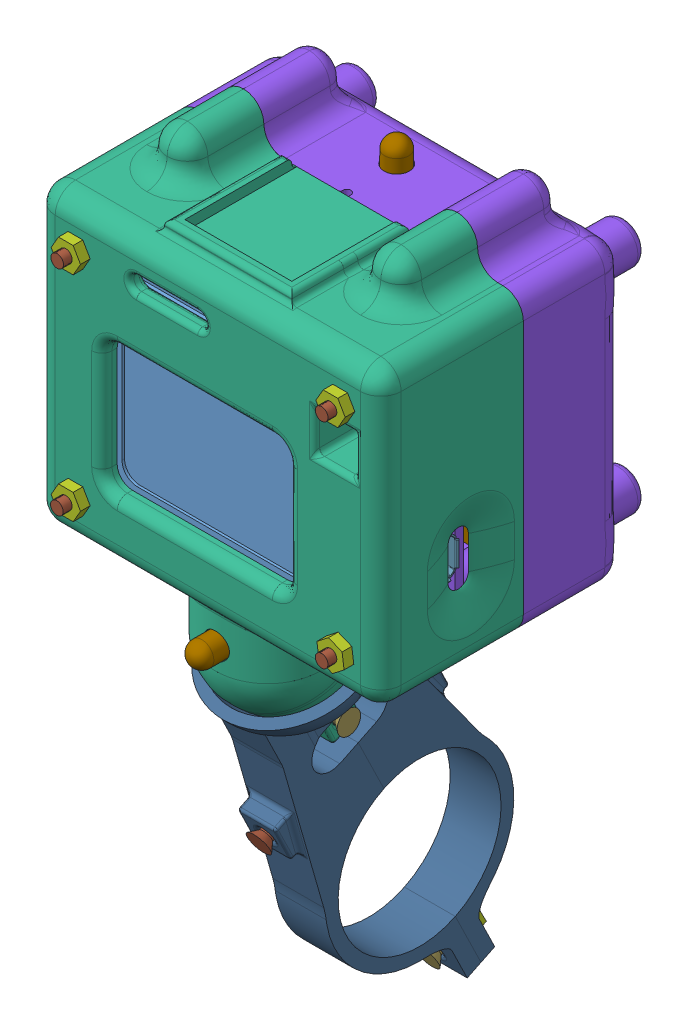
SolidWorks assembly 外壳装配体, configuration 默认. Lengths in mm.
Overall size (68.01 154.06 68.95).
141 component instances, 29 part files, 72 mates.
Components (placement in the parent):
- LCD5110-1: LCD5110 [默认] at (0 0 1.2) size (42.32 45.5 15)
- GPS-1: GPS [默认] x (-1 0 0) z (0 0 -1) size (16 13.5 12.2)
- SIM800L-1: SIM800L [默认] x (-1 0 0) z (0 0 -1) size (40 27.78 12.6)
- M3双通铜柱-1: M3双通铜柱 [默认] at (-25.1238 -0.1501 1.2) size (4.59 5.3 11.22)
- M3双通铜柱-2: M3双通铜柱 [默认] at (16.8947 -71.0684 1.2) x (0.866025 0.5 0) z (0 0 1) size (4.59 5.3 11.22)
- M3双通铜柱-3: M3双通铜柱 [默认] at (60.3287 -26.8877 1.2) x (0.242096 0.970252 0) z (0 0 1) size (4.59 5.3 11.22)
- M3双通铜柱-4: M3双通铜柱 [默认] at (-33.2302 -25.3619 -11) size (4.59 5.3 11.22)
- M3双通铜柱-5: M3双通铜柱 [默认] at (73.8252 -17.7107 -11) x (0 1 0) z (0 0 1) size (4.59 5.3 11.22)
- M3双通铜柱-6: M3双通铜柱 [默认] at (-17.5653 -71.0684 1.2) x (0.866025 0.5 0) z (0 0 1) size (4.59 5.3 11.22)
- M3双通铜柱-7: M3双通铜柱 [默认] at (8.7882 -34.0691 -11) x (0.866025 0.5 0) z (0 0 1) size (4.59 5.3 11.22)
- M3x3-1: M3x3 [默认] at (17.4869 22.3607 12.2) x (1 0 0) z (0 1 0) size (6 4.18 6)
- M3x3-2: M3x3 [默认] at (51.9469 22.3607 12.2) x (1 0 0) z (0 1 0) size (6 4.18 6)
- M3x3-3: M3x3 [默认] at (43.8405 59.3599 -11.6) x (1 0 0) z (0 -1 0) size (6 4.18 6)
- M3x3-4: M3x3 [默认] at (43.8405 38.0239 -11.6) x (1 0 0) z (0 -1 0) size (6 4.18 6)
- M3x3-5: M3x3 [默认] at (10.4394 59.3599 -11.6) x (1 0 0) z (0 -1 0) size (6 4.18 6)
- M3x3-6: M3x3 [默认] at (43.8405 59.3599 0.2) x (1 0 0) z (0 1 0) size (6 4.18 6)
- M3x3-7: M3x3 [默认] at (10.4394 59.3599 0.2) x (1 0 0) z (0 1 0) size (6 4.18 6)
- M3x3-8: M3x3 [默认] at (43.8405 38.0239 0.2) x (1 0 0) z (0 1 0) size (6 4.18 6)
- M3x3-9: M3x3 [默认] at (17.4869 22.3607 1) x (1 0 0) z (0 -1 0) size (6 4.18 6)
- M3x3-10: M3x3 [默认] at (17.4869 63.2357 1) x (1 0 0) z (0 -1 0) size (6 4.18 6)
- M3x3-11: M3x3 [默认] at (51.9469 63.2357 1) x (1 0 0) z (0 -1 0) size (6 4.18 6)
- M3x3-12: M3x3 [默认] at (51.9469 22.3607 1) x (1 0 0) z (0 -1 0) size (6 4.18 6)
- 外壳-上-1: 外壳-上 [默认] at (0.051 -0.0812 1.2) size (68.01 96.44 34)
- M2.5螺母-1: M2.5螺母 [默认] at (63.051 23.9188 20.2) x (-0.926094 0.377293 0) z (0 0 1) size (5.77 5 1.9)
- M2.5螺母-3: M2.5螺母 [默认] at (63.051 65.9188 20.2) size (5.77 5 1.9)
- 外壳-下-1: 外壳-下 [默认] at (0.051 -0.0812 -7.8) x (-1 0 0) z (0 0 -1) size (67.97 73.97 35.69)
- SIM天线-1: SIM天线 [默认] at (56.801 27.4315 -24.8) x (0 0 -1) z (-1 0 0) size (10.5 53 28.75)
- GPS天线-1: GPS天线 [默认] at (16.7214 57.8639 -16.8) x (-1 0 0) z (0 0 -1) size (28 27 8)
- M2.5x60-1: M2.5x60 [默认] at (63.051 65.9188 -26.1568) x (0 0 -1) z (0.717913 -0.696133 0) size (60 4.6 4.6)
- M2.5x60-2: M2.5x60 [默认] at (63.051 23.9188 -26.1568) x (0 0 -1) z (0.71399 -0.700156 0) size (60 4.6 4.6)
- M2.5x60-3: M2.5x60 [默认] at (11.051 23.9188 -26.14) x (0 0 -1) z (0.842989 0.537931 0) size (60 4.6 4.6)
- M2.5x60-4: M2.5x60 [默认] at (11.051 65.9188 -26.2005) x (0 0 -1) z (0.861499 -0.507759 0) size (60 4.6 4.6)
- M2.5螺母-4: M2.5螺母 [默认] at (11.051 65.9188 20.2) size (5.77 5 1.9)
- M2.5螺母-5: M2.5螺母 [默认] at (11.051 23.9188 20.2) size (5.77 5 1.9)
- M2.5x10-1: M2.5x10 [默认] at (31.551 -10.7286 -3.0168) x (1 0 0) z (0 -0.509192 0.860653) size (10 4.6 4.6)
- M2.5螺母-6: M2.5螺母 [默认] at (32.151 -10.7286 -3.0168) x (0 -0.102838 -0.994698) z (1 0 0) size (5.77 5 1.9)
- M2.5螺母-7: M2.5螺母 [默认] at (11.051 65.9188 3.5) x (0.136618 0.990624 0) z (0 0 -1) size (5.77 5 1.9)
- M2.5螺母-8: M2.5螺母 [默认] at (11 24 3.1) x (0.136618 0.990624 0) z (0 0 -1) size (5.77 5 1.9)
- PCB_NG.step-1: PCB_NG.step [默认] at (0.051 -0.0812 0) size (60.71 51.17 22.75)
  - C4.step-1: C4.step [默认] at (62.3571 42.1641 1.6) x (0 1 0) z (0 0 1) size (1.6 0.8 0.8)
    - C0603.step-1: C0603.step [默认] at origin size (1.6 0.8 0.8)
      - SOLID.step-1: SOLID.step [默认] at origin size (1.6 0.8 0.8)
  - C1.step-1: C1.step [默认] at (52.1971 47.1171 1.6) size (1.6 0.8 0.8)
    - C0603.step-1: C0603.step [默认] at origin size (1.6 0.8 0.8)
      - SOLID.step-1: SOLID.step [默认] at origin size (1.6 0.8 0.8)
  - C2.step-1: C2.step [默认] at (11.938 50.0381 1.6) x (0 1 0) z (0 0 1) size (1.6 0.8 0.8)
    - C0603.step-1: C0603.step [默认] at origin size (1.6 0.8 0.8)
      - SOLID.step-1: SOLID.step [默认] at origin size (1.6 0.8 0.8)
  - C3.step-1: C3.step [默认] at (27.1781 59.8171 1.6) size (1.6 0.8 0.8)
    - C0603.step-1: C0603.step [默认] at origin size (1.6 0.8 0.8)
      - SOLID.step-1: SOLID.step [默认] at origin size (1.6 0.8 0.8)
  - C5.step-1: C5.step [默认] at (28.1941 43.3071 1.6) x (0 -1 0) z (0 0 1) size (1.6 0.8 0.8)
    - C0603.step-1: C0603.step [默认] at origin size (1.6 0.8 0.8)
      - SOLID.step-1: SOLID.step [默认] at origin size (1.6 0.8 0.8)
  - C6.step-1: C6.step [默认] at (34.6711 53.2131 1.6) size (1.6 0.8 0.8)
    - C0603.step-1: C0603.step [默认] at origin size (1.6 0.8 0.8)
      - SOLID.step-1: SOLID.step [默认] at origin size (1.6 0.8 0.8)
  - C7.step-1: C7.step [默认] at (44.4501 48.5141 1.6) x (0 1 0) z (0 0 1) size (1.6 0.8 0.8)
    - C0603.step-1: C0603.step [默认] at origin size (1.6 0.8 0.8)
      - SOLID.step-1: SOLID.step [默认] at origin size (1.6 0.8 0.8)
  - C8.step-1: C8.step [默认] at (38.2271 26.6701 1.6) x (0 -1 0) z (0 0 1) size (1.6 0.8 0.8)
    - C0603.step-1: C0603.step [默认] at origin size (1.6 0.8 0.8)
      - SOLID.step-1: SOLID.step [默认] at origin size (1.6 0.8 0.8)
  - C9.step-1: C9.step [默认] at (17.526 42.0371 1.6) x (0 1 0) z (0 0 1) size (1.6 0.8 0.8)
    - C0603.step-1: C0603.step [默认] at origin size (1.6 0.8 0.8)
      - SOLID.step-1: SOLID.step [默认] at origin size (1.6 0.8 0.8)
  - C10.step-1: C10.step [默认] at (30.0991 39.1161 1.6) x (-1 0 0) z (0 0 1) size (1.6 0.8 0.8)
    - C0603.step-1: C0603.step [默认] at origin size (1.6 0.8 0.8)
      - SOLID.step-1: SOLID.step [默认] at origin size (1.6 0.8 0.8)
  - ADC.step-1: ADC.step [默认] at (58.6741 23.495 1.6) x (0 1 0) z (0 0 1) size (8 5.68 3.68)
    - HDR-F-2.54_1X2.step-1: HDR-F-2.54_1X2.step [默认] at origin size (8 5.68 3.68)
      - COMPOUND.step-1: COMPOUND.step [默认] at origin size (8 5.68 3.68)
  - POS.step-1: POS.step [默认] at (16.51 68.5801 1.6) size (8 5.68 3.68)
    - HDR-F-2.54_1X2.step-1: HDR-F-2.54_1X2.step [默认] at origin size (8 5.68 3.68)
      - COMPOUND.step-1: COMPOUND.step [默认] at origin size (8 5.68 3.68)
  - R1.step-1: R1.step [默认] at (50.5461 68.5801 1.6) x (-1 0 0) z (0 0 1) size (1.6 0.8 0.8)
    - R0603.step-1: R0603.step [默认] at origin size (1.6 0.8 0.8)
      - SOLID-3.step-1: SOLID-3.step [默认] at origin size (1.6 0.8 0.8)
  - SW2.step-1: SW2.step [默认] at (10.541 33.0199 1.6) x (0 1 0) z (0 0 1) size (6.5 4.5 7.5)
    - SW-SMD_4P-L4.5-W4.5-P3.00-LS7.0.step-1: SW-SMD_4P-L4.5-W4.5-P3.00-LS7.0.step [默认] at origin size (6.5 4.5 7.5)
      - COMPOUND-1.step-1: COMPOUND-1.step [默认] at origin size (6.5 4.5 7.5)
  - LED1.step-1: LED1.step [默认] at (40.7671 68.5801 1.6) x (-1 0 0) z (0 0 1) size (3 1.51 1)
    - LED1206-RD.step-1: LED1206-RD.step [默认] at origin size (3 1.51 1)
      - COMPOUND-4.step-1: COMPOUND-4.step [默认] at origin size (3 1.51 1)
  - SW1.step-1: SW1.step [默认] at (61.9761 58.4201 1.6) x (0 1 0) z (0 0 1) size (7 7 16.2)
    - KEY-TH_6P-L7.0-W7.0-P2.00.step-1: KEY-TH_6P-L7.0-W7.0-P2.00.step [默认] at origin size (7 7 16.2)
      - COMPOUND-0.step-1: COMPOUND-0.step [默认] at origin size (7 7 16.2)
  - U6.step-1: U6.step [默认] at (33.7821 28.9561 0) x (-1 0 0) z (0 0 -1) size (7.2 6.6 7.72)
    - CAP-SMD_BD6.3-L6.6-W6.6-LS7.2-FD.step-1: CAP-SMD_BD6.3-L6.6-W6.6-LS7.2-FD.step [默认] at origin size (7.2 6.6 7.72)
      - SOLID-4.step-1: SOLID-4.step [默认] at origin size (7.2 6.6 7.72)
  - R2.step-1: R2.step [默认] at (54.2291 26.5431 1.6) size (15.24 2.54 11.5)
    - R0603-1.step-1: R0603-1.step [默认] at origin size (15.24 2.54 11.5)
      - COMPOUND-5.step-1: COMPOUND-5.step [默认] at origin size (15.24 2.54 11.5)
  - R3.step-1: R3.step [默认] at (51.0541 26.5431 1.6) size (15.24 2.54 11.5)
    - R0603-1.step-1: R0603-1.step [默认] at origin size (15.24 2.54 11.5)
      - COMPOUND-5.step-1: COMPOUND-5.step [默认] at origin size (15.24 2.54 11.5)
  - R4.step-1: R4.step [默认] at (48.2601 23.368 1.6) size (15.24 2.54 11.5)
    - R0603-1.step-1: R0603-1.step [默认] at origin size (15.24 2.54 11.5)
      - COMPOUND-5.step-1: COMPOUND-5.step [默认] at origin size (15.24 2.54 11.5)
  - R16.step-1: R16.step [默认] at (21.971 59.1821 0) x (-1 0 0) z (0 0 -1) size (15.24 2.54 11.5)
    - R0603-1.step-1: R0603-1.step [默认] at origin size (15.24 2.54 11.5)
      - COMPOUND-5.step-1: COMPOUND-5.step [默认] at origin size (15.24 2.54 11.5)
  - R17.step-1: R17.step [默认] at (21.971 56.0071 0) x (-1 0 0) z (0 0 -1) size (15.24 2.54 11.5)
    - R0603-1.step-1: R0603-1.step [默认] at origin size (15.24 2.54 11.5)
      - COMPOUND-5.step-1: COMPOUND-5.step [默认] at origin size (15.24 2.54 11.5)
  - R18.step-1: R18.step [默认] at (21.971 63.8811 0) x (-1 0 0) z (0 0 -1) size (15.24 2.54 11.5)
    - R0603-1.step-1: R0603-1.step [默认] at origin size (15.24 2.54 11.5)
      - COMPOUND-5.step-1: COMPOUND-5.step [默认] at origin size (15.24 2.54 11.5)
  - C11.step-1: C11.step [默认] at (44.1961 30.3531 1.6) x (0 1 0) z (0 0 1) size (3.05 2.6 9.5)
    - CAP-TH_L3.5-W3.0-P2.54-D0.8.step-1: CAP-TH_L3.5-W3.0-P2.54-D0.8.step [默认] at origin size (3.05 2.6 9.5)
      - SOLID-6.step-1: SOLID-6.step [默认] at origin size (3.05 2.6 9.5)
  - C13.step-1: C13.step [默认] at (26.6701 34.6711 1.6) x (0 1 0) z (0 0 1) size (3.05 2.6 9.5)
    - CAP-TH_L3.5-W3.0-P2.54-D0.8.step-1: CAP-TH_L3.5-W3.0-P2.54-D0.8.step [默认] at origin size (3.05 2.6 9.5)
      - SOLID-6.step-1: SOLID-6.step [默认] at origin size (3.05 2.6 9.5)
  - C12.step-1: C12.step [默认] at (17.272 32.8931 1.6) x (-1 0 0) z (0 0 1) size (2 1.3 1.3)
    - C0805.step-1: C0805.step [默认] at origin size (2 1.3 1.3)
      - SOLID-2.step-1: SOLID-2.step [默认] at origin size (2 1.3 1.3)
  - CN1.step-1: CN1.step [默认] at (64.1344 33.4014 1.6) x (0 1 0) z (0 0 1) size (8 5.68 3.68)
    - MICRO-USB_FEMALE_A01SB.step-1: MICRO-USB_FEMALE_A01SB.step [默认] at origin size (8 5.68 3.68)
      - COMPOUND.step-1: COMPOUND.step [默认] at origin size (8 5.68 3.68)
  - U5.step-1: U5.step [默认] at (52.1971 56.2611 1.6) size (7.11 6.5 1.75)
    - SOT-223-4_L6.5-W3.5-P2.30-LS7.0-BR.step-1: SOT-223-4_L6.5-W3.5-P2.30-LS7.0-BR.step [默认] at origin size (7.11 6.5 1.75)
      - COMPOUND-6.step-1: COMPOUND-6.step [默认] at origin size (7.11 6.5 1.75)
  - H1.step-1: H1.step [默认] at (26.6701 68.5801 1.6) size (15.24 2.54 11.5)
    - HDR-F-2.54_1X6.step-1: HDR-F-2.54_1X6.step [默认] at origin size (15.24 2.54 11.5)
      - COMPOUND-5.step-1: COMPOUND-5.step [默认] at origin size (15.24 2.54 11.5)
  - Q4.step-1: Q4.step [默认] at (17.272 57.9121 0) x (0 -1 0) z (0 0 -1) size (2.51 2.9 1.05)
    - SOT-23_L2.9-W1.3-P1.90-LS2.4-BR.step-1: SOT-23_L2.9-W1.3-P1.90-LS2.4-BR.step [默认] at origin size (2.51 2.9 1.05)
      - COMPOUND-11.step-1: COMPOUND-11.step [默认] at origin size (2.51 2.9 1.05)
  - U1.step-1: U1.step [默认] at (36.8301 45.7201 1.6) size (9 9 1.45)
    - LQFP-48_L7.0-W7.0-P0.50-LS9.0-BL.step-1: LQFP-48_L7.0-W7.0-P0.50-LS9.0-BL.step [默认] at origin size (9 9 1.45)
      - COMPOUND-7.step-1: COMPOUND-7.step [默认] at origin size (9 9 1.45)
  - COMPOUND-13.step-1: COMPOUND-13.step [默认] at origin size (59.97 49.97 1.6)
- LED-1: LED [默认] at (35.8637 70.4061 -18.1) x (0.999835 0 -0.018168) z (0 1 0) size (5.4 5.4 21.4)
- LED-2: LED [默认] at (37.051 10.9315 15.3381) x (-0.018882 0.999822 0) z (0 0 1) size (5.4 5.4 21.4)
- 外壳基座-1: 外壳基座 [默认] at (37.051 78.865 41.2372) x (0 -0.438371 0.898794) z (-1 0 0) size (18.5 75.84 28.01)
- 外壳基座-2: 外壳基座 [默认] at (37.051 78.865 41.2372) x (0 0.438371 -0.898794) z (1 0 0) size (18.5 75.84 28.01)
- M2.5x40-1: M2.5x40 [默认] at (37.051 -22.6499 1.1822) x (0 -0.438371 0.898794) z (0.65672 -0.677811 -0.330591) size (40 4.6 4.6)
- M2.5x10-4: M2.5x10 [默认] at (37.051 -58.5763 -31.9167) x (0 -0.438371 0.898794) z (-0.384685 0.82963 0.404638) size (10 4.6 4.6)
- M2.5螺母-11: M2.5螺母 [默认] at (37.051 -10.6385 -23.4448) x (0.054672 -0.89745 -0.437716) z (0 -0.438371 0.898794) size (5.77 5 1.9)
- M2.5螺母-12: M2.5螺母 [默认] at (37.051 -58.8393 -31.3774) x (0.054672 -0.89745 -0.437716) z (0 -0.438371 0.898794) size (5.77 5 1.9)
Mates (geometry in assembly coordinates):
- 重合20: coincident anti-aligned: plane of LCD5110-1 through (0 0 12.2) normal (0 0 -1); plane of M3双通铜柱-1 through (-25.1238 -0.1501 12.2) normal (0 0 1)
- 同心1: concentric aligned: circle of LCD5110-1; unknown of M3双通铜柱-1
- 重合22: coincident anti-aligned: plane of LCD5110-1 through (0 0 12.2) normal (0 0 -1); plane of M3双通铜柱-2 through (16.8947 -71.0684 12.2) normal (0 0 1)
- 同心2: concentric aligned: unknown of LCD5110-1; unknown of M3双通铜柱-2
- 重合24: coincident anti-aligned: plane of LCD5110-1 through (0 0 12.2) normal (0 0 -1); plane of M3双通铜柱-6 through (-17.5653 -71.0684 12.2) normal (0 0 1)
- 同心3: concentric aligned: unknown of LCD5110-1; unknown of M3双通铜柱-6
- 重合26: coincident anti-aligned: plane of LCD5110-1 through (0 0 12.2) normal (0 0 -1); plane of M3双通铜柱-3 through (60.3287 -26.8877 12.2) normal (0 0 1)
- 同心4: concentric aligned: unknown of LCD5110-1; unknown of M3双通铜柱-3
- 重合29: coincident anti-aligned: plane of SIM800L-1 through (0 0 -11) normal (0 0 1); plane of M3双通铜柱-4 through (-33.2302 -25.3619 -11) normal (0 0 -1)
- 同心6: concentric anti-aligned: unknown of SIM800L-1; unknown of M3双通铜柱-4
- 同心7: concentric anti-aligned: unknown of SIM800L-1; unknown of M3双通铜柱-7
- 同心8: concentric anti-aligned: unknown of SIM800L-1; unknown of M3双通铜柱-5
- 平行4: parallel aligned: plane of SIM800L-1 through (7.728 62.3721 -12.6) normal (0 1 0); plane of M3双通铜柱-7 through (45.1655 61.6549 0) normal (0 1 0)
- 平行5: parallel aligned: plane of SIM800L-1 through (7.728 62.3721 -12.6) normal (0 1 0); plane of M3双通铜柱-5 through (11.7644 61.6549 0) normal (0 1 0)
- 重合37: coincident anti-aligned: plane of LCD5110-1 through (0 0 13.2) normal (0 0 1); plane of M3x3-2 through (48.9469 22.3607 13.2) normal (0 0 -1)
- 同心11: concentric aligned: unknown of LCD5110-1; unknown of M3x3-2
- 重合38: coincident anti-aligned: plane of LCD5110-1 through (0 0 13.2) normal (0 0 1); plane of M3x3-1 through (14.4869 22.3607 13.2) normal (0 0 -1)
- 同心12: concentric aligned: unknown of LCD5110-1; unknown of M3x3-1
- 重合39: coincident anti-aligned: plane of SIM800L-1 through (0 0 -12.6) normal (0 0 -1); plane of M3x3-3 through (40.8405 59.3599 -12.6) normal (0 0 1)
- 重合40: coincident anti-aligned: plane of SIM800L-1 through (0 0 -12.6) normal (0 0 -1); plane of M3x3-4 through (40.8405 38.0239 -12.6) normal (0 0 1)
- 重合41: coincident anti-aligned: plane of SIM800L-1 through (0 0 -12.6) normal (0 0 -1); plane of M3x3-5 through (7.4394 59.3599 -12.6) normal (0 0 1)
- 同心13: concentric aligned: unknown of SIM800L-1; unknown of M3x3-3
- 同心14: concentric aligned: unknown of SIM800L-1; unknown of M3x3-4
- 同心15: concentric aligned: unknown of SIM800L-1; unknown of M3x3-5
- 重合58: coincident anti-aligned: plane of 外壳-上-1 through (0.051 -0.0812 20.2) normal (0 0 1); plane of M2.5螺母-1 through (63.051 23.9188 20.2) normal (0 0 -1)
- 同心25: concentric anti-aligned: unknown of 外壳-上-1; unknown of M2.5螺母-1
- 重合59: coincident anti-aligned: plane of 外壳-上-1 through (0.051 -0.0812 20.2) normal (0 0 1); plane of M2.5螺母-3 through (63.051 65.9188 20.2) normal (0 0 -1)
- 同心26: concentric anti-aligned: unknown of 外壳-上-1; unknown of M2.5螺母-3
- 同心28: concentric anti-aligned: unknown of 外壳-下-1; unknown of M2.5x60-2
- 同心29: concentric anti-aligned: unknown of 外壳-下-1; unknown of M2.5x60-1
- 同心30: concentric aligned: unknown of M2.5螺母-3; unknown of M2.5x60-1
- 同心31: concentric aligned: unknown of M2.5螺母-1; unknown of M2.5x60-2
- 平行7: parallel aligned: plane of M2.5x60-1 through (64.6521 67.57 -36.1568) normal (0 0 -1); plane of M2.5x60-2 through (64.6614 25.5609 -36.1568) normal (0 0 -1)
- 重合78: coincident aligned: plane of M2.5x60-1 through (64.6521 67.57 -36.1568) normal (0 0 -1); plane of M2.5x60-2 through (64.6614 25.5609 -36.1568) normal (0 0 -1)
- 同心32: concentric anti-aligned: unknown of 外壳-下-1; unknown of M2.5x60-4
- 同心33: concentric anti-aligned: unknown of 外壳-下-1; unknown of M2.5x60-3
- 重合80: coincident anti-aligned: plane of 外壳-上-1 through (0.051 -0.0812 20.2) normal (0 0 1); plane of M2.5螺母-4 through (11.051 65.9188 20.2) normal (0 0 -1)
- 同心34: concentric anti-aligned: unknown of 外壳-上-1; unknown of M2.5螺母-4
- 重合81: coincident anti-aligned: plane of 外壳-上-1 through (0.051 -0.0812 20.2) normal (0 0 1); plane of M2.5螺母-5 through (11.051 23.9188 20.2) normal (0 0 -1)
- 同心35: concentric anti-aligned: unknown of 外壳-上-1; unknown of M2.5螺母-5
- 重合82: coincident anti-aligned: plane of 外壳-下-1 through (0.051 -0.0812 -24.8) normal (0 0 1); plane of SIM天线-1 through (29.801 27.4315 -24.8) normal (0 0 -1)
- 重合83: coincident anti-aligned: plane of 外壳-下-1 through (68.5383 18.4315 -24.8) normal (0 1 0); plane of SIM天线-1 through (29.801 18.4315 -24.8) normal (0 -1 0)
- 相切1: tangent anti-aligned: cylinder of 外壳-下-1; cylinder of SIM天线-1 through (53.301 71.4315 -20.3) axis (0 -1 0) radius 5.25
- 重合84: coincident anti-aligned: plane of 外壳-下-1 through (0.051 -0.0812 -24.8) normal (0 0 1); plane of GPS天线-1 through (16.7214 57.8639 -24.8) normal (0 0 -1)
- 重合93: coincident anti-aligned: plane of 外壳-上-1 through (0.051 -0.0812 -7.8) normal (0 0 -1); plane of 外壳-下-1 through (0.051 -0.0812 -7.8) normal (0 0 1)
- 同心39: concentric aligned: unknown of 外壳-下-1; unknown of PCB_NG.step-1/COMPOUND-13.step-1
- 同心40: concentric aligned: unknown of 外壳-下-1; unknown of PCB_NG.step-1/COMPOUND-13.step-1
- 重合95: coincident anti-aligned: plane of 外壳-下-1 through (11.051 65.9188 0) normal (0 0 1); plane of PCB_NG.step-1/COMPOUND-13.step-1 through (37.051 44.9188 0) normal (0 0 -1)
- 同心41: concentric anti-aligned: unknown of M2.5螺母-7; unknown of PCB_NG.step-1/COMPOUND-13.step-1
- 重合96: coincident anti-aligned: plane of M2.5螺母-7 through (11.051 65.9188 1.6) normal (0 0 -1); plane of PCB_NG.step-1/COMPOUND-13.step-1 through (37.051 44.9188 1.6) normal (0 0 1)
- 同心43: concentric anti-aligned: cylinder of 外壳-下-1 through (35.8637 7.9305 -18.1) axis (0 1 0) radius 2.5; cylinder of LED-1 through (35.8637 70.4061 -18.1) axis (0 -1 0) radius 2.36
- 重合100: coincident anti-aligned: plane of 外壳-下-1 through (5.5637 71.4061 -24.8) normal (0 -1 0); plane of LED-1 through (38.2233 71.4061 -18.1429) normal (0 1 0)
- 重合103: coincident anti-aligned: plane of 外壳-上-1 through (40.051 65.6045 37.5511) normal (1 0 0); unknown of M2.5x10-1
- 同心46: concentric anti-aligned: unknown of M2.5x10-1; unknown of M2.5螺母-6
- 重合104: coincident anti-aligned: plane of 外壳-上-1 through (34.051 68.2348 32.1584) normal (-1 0 0); plane of M2.5螺母-6 through (34.051 -10.7286 -3.0168) normal (1 0 0)
- 同心47: concentric anti-aligned: unknown of 外壳-下-1; cylinder of LED-1 through (35.8637 70.4061 -18.1) axis (0 -1 0) radius 2.36
- 同心48: concentric anti-aligned: cylinder of 外壳-上-1 through (37.051 10.9315 -13.801) axis (0 0 1) radius 2.5; cylinder of LED-2 through (37.051 10.9315 15.3381) axis (0 0 -1) radius 2.7
- 平行10: parallel aligned: plane of 外壳-上-1 through (40.051 -12.1098 -7.0283) normal (0 -0.898794 -0.438371); plane of 外壳基座-2 through (37.051 -7.8686 -1.0656) normal (0 -0.898794 -0.438371)
- 重合110: coincident anti-aligned: plane of 外壳基座-1 through (42.051 -22.6987 -8.2987) normal (0 0.438371 -0.898794); plane of 外壳基座-2 through (32.051 -22.6987 -8.2987) normal (0 -0.438371 0.898794)
- 同心56: concentric: sphere of 外壳-上-1; unknown of 外壳基座-1
- 同心63: concentric anti-aligned: unknown of 外壳-上-1; unknown of M2.5x10-1
- 重合111: coincident anti-aligned: plane of 外壳基座-1 through (37.051 71.4127 56.5167) normal (0 -0.438371 0.898794); unknown of M2.5x40-1
- 同心67: concentric anti-aligned: unknown of 外壳基座-1; unknown of 外壳基座-2
- 同心68: concentric anti-aligned: unknown of 外壳基座-1; unknown of 外壳基座-2
- 同心69: concentric anti-aligned: unknown of 外壳基座-1; unknown of M2.5x40-1
- 同心70: concentric anti-aligned: unknown of 外壳基座-1; unknown of M2.5x10-4
- 重合112: coincident anti-aligned: plane of 外壳基座-1 through (42.051 -65.3583 -25.7674) normal (0 -0.438371 0.898794); unknown of M2.5x10-4
- 同心71: concentric anti-aligned: unknown of M2.5x40-1; unknown of M2.5螺母-11
- 重合113: coincident anti-aligned: plane of 外壳基座-2 through (37.051 86.3173 25.9577) normal (0 0.438371 -0.898794); plane of M2.5螺母-11 through (37.051 -11.4715 -21.7371) normal (0 -0.438371 0.898794)
- 同心72: concentric anti-aligned: unknown of M2.5x10-4; unknown of M2.5螺母-12
- 重合114: coincident anti-aligned: plane of 外壳基座-2 through (32.051 -62.7281 -31.1602) normal (0 0.438371 -0.898794); plane of M2.5螺母-12 through (37.051 -59.6722 -29.6697) normal (0 -0.438371 0.898794)
- 平行11: parallel aligned: line of 外壳-上-1 through (49.698 25.7015 20.2) axis (-1 0 0); line of 外壳基座-1 through (40.051 -23.4101 10.2685) axis (-1 0 0)
